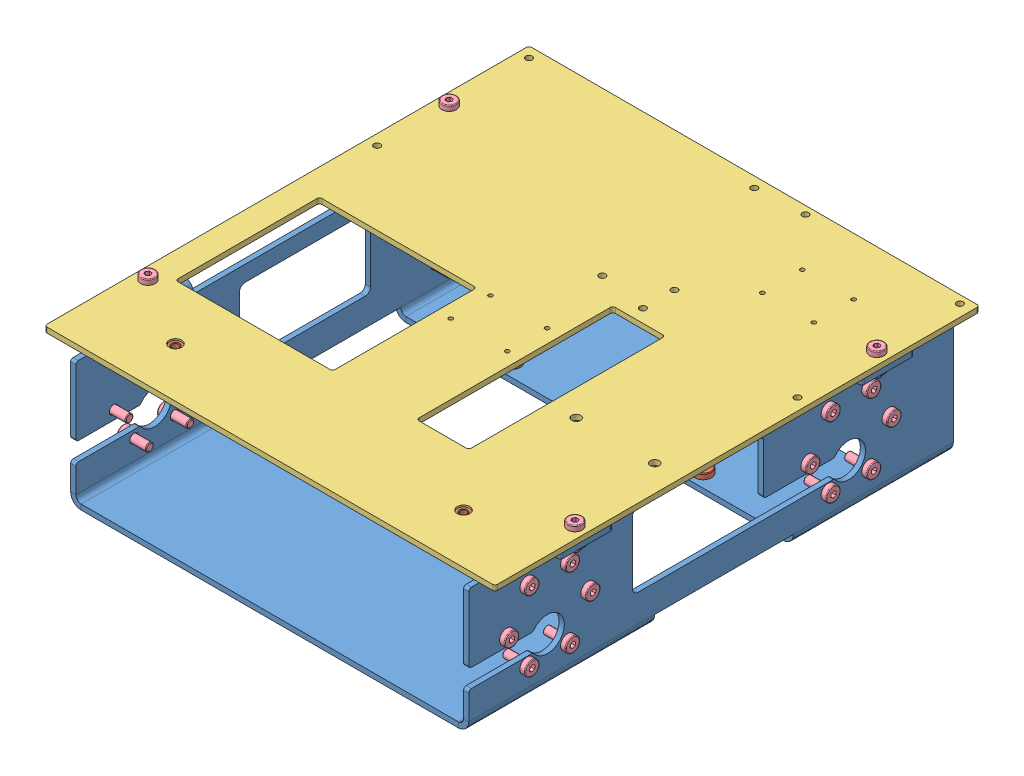
SolidWorks assembly HEL-03-01007-00, configuration Standard. Lengths in mm.
Overall size (172 56 193.5).
44 component instances, 4 part files, 77 mates.
Components (placement in the parent):
- HEL-03-01009-00-1: HEL-03-01009-00 [Standard] at origin size (172 52 193.5)
  - HEL-04-01000-02-1: HEL-04-01000-02 [Standard] at origin size (172 52 193.5)
  - aluminum nut_pmm-11: aluminum nut_pmm [PEM CLA-M3-2 ---N] at (81.5 48 -150) x (0.837169 0 0.546944) z (0.546944 0 -0.837169) size (6.3 3.37 6.3)
  - aluminum nut_pmm-12: aluminum nut_pmm [PEM CLA-M3-2 ---N] at (81.5 48 -35) x (0.837169 0 0.546944) z (0.546944 0 -0.837169) size (6.3 3.37 6.3)
  - aluminum nut_pmm-13: aluminum nut_pmm [PEM CLA-M3-2 ---N] at (-81.5 48 -150) x (0.837169 0 0.546944) z (0.546944 0 -0.837169) size (6.3 3.37 6.3)
  - aluminum nut_pmm-14: aluminum nut_pmm [PEM CLA-M3-2 ---N] at (-81.5 48 -35) x (0.837169 0 0.546944) z (0.546944 0 -0.837169) size (6.3 3.37 6.3)
  - aluminum nut_pmm-15: aluminum nut_pmm [PEM CLA-M3-2 ---N] at (29 6 -191.5) x (1 0 0) z (0 -1 0) size (6.3 3.37 6.3)
  - aluminum nut_pmm-16: aluminum nut_pmm [PEM CLA-M3-2 ---N] at (-29 6 -191.5) x (1 0 0) z (0 -1 0) size (6.3 3.37 6.3)
  - aluminum nut_pmm-17: aluminum nut_pmm [PEM CLA-M3-2 ---N] at (-36.5 0 -129) size (6.3 3.37 6.3)
  - aluminum nut_pmm-18: aluminum nut_pmm [PEM CLA-M3-2 ---N] at (-36.5 0 -66) size (6.3 3.37 6.3)
  - aluminum nut_pmm-19: aluminum nut_pmm [PEM CLA-M3-2 ---N] at (36.5 0 -66) size (6.3 3.37 6.3)
  - aluminum nut_pmm-20: aluminum nut_pmm [PEM CLA-M3-2 ---N] at (36.5 0 -129) x (-0.993512 0 -0.113726) z (0.113726 0 -0.993512) size (6.3 3.37 6.3)
- HEL-03-01010-00-1: HEL-03-01010-00 [Standard] at (0 50 -92.5) size (172 4 185)
  - HEL-04-01010-01-1: HEL-04-01010-01 [Standard] at origin size (172 2 185)
  - aluminum nut_pmm-1: aluminum nut_pmm [PEM CLA-M3-2 ---N] at (55 0 73.5) x (0.837169 0 0.546944) z (0.546944 0 -0.837169) size (6.3 3.37 6.3)
  - aluminum nut_pmm-2: aluminum nut_pmm [PEM CLA-M3-2 ---N] at (-55 0 73.5) x (0.837169 0 0.546944) z (0.546944 0 -0.837169) size (6.3 3.37 6.3)
- socket head thin cap screw_din-1: socket head thin cap screw_din [DIN 7984 - M3 x 8 --- 8N] at (-81.5 54 -35) x (0 -1 0) z (-0.091641 0 0.995792) size (10 5.5 5.5)
- socket head thin cap screw_din-6: socket head thin cap screw_din [DIN 7984 - M3 x 8 --- 8N] at (-78 36.4234 -37.75) size (10 5.5 5.5)
- socket head thin cap screw_din-7: socket head thin cap screw_din [DIN 7984 - M3 x 8 --- 8N] at (-78 36.4234 -22.25) size (10 5.5 5.5)
- socket head thin cap screw_din-8: socket head thin cap screw_din [DIN 7984 - M3 x 8 --- 8N] at (-78 23 -45.5) size (10 5.5 5.5)
- socket head thin cap screw_din-9: socket head thin cap screw_din [DIN 7984 - M3 x 8 --- 8N] at (-78 23 -14.5) size (10 5.5 5.5)
- socket head thin cap screw_din-10: socket head thin cap screw_din [DIN 7984 - M3 x 8 --- 8N] at (-78 9.5766 -22.25) size (10 5.5 5.5)
- socket head thin cap screw_din-11: socket head thin cap screw_din [DIN 7984 - M3 x 8 --- 8N] at (-78 9.5766 -37.75) size (10 5.5 5.5)
- socket head thin cap screw_din-12: socket head thin cap screw_din [DIN 7984 - M3 x 8 --- 8N] at (-78 9.5766 -137.25) size (10 5.5 5.5)
- socket head thin cap screw_din-13: socket head thin cap screw_din [DIN 7984 - M3 x 8 --- 8N] at (-78 9.5766 -152.75) size (10 5.5 5.5)
- socket head thin cap screw_din-14: socket head thin cap screw_din [DIN 7984 - M3 x 8 --- 8N] at (-78 23 -160.5) size (10 5.5 5.5)
- socket head thin cap screw_din-15: socket head thin cap screw_din [DIN 7984 - M3 x 8 --- 8N] at (-78 36.4234 -152.75) size (10 5.5 5.5)
- socket head thin cap screw_din-16: socket head thin cap screw_din [DIN 7984 - M3 x 8 --- 8N] at (-78 36.4234 -137.25) size (10 5.5 5.5)
- socket head thin cap screw_din-17: socket head thin cap screw_din [DIN 7984 - M3 x 8 --- 8N] at (-78 23 -129.5) size (10 5.5 5.5)
- socket head thin cap screw_din-18: socket head thin cap screw_din [DIN 7984 - M3 x 8 --- 8N] at (78 36.4234 -37.75) x (-1 0 0) z (0 0.924225 0.381849) size (10 5.5 5.5)
- socket head thin cap screw_din-19: socket head thin cap screw_din [DIN 7984 - M3 x 8 --- 8N] at (78 36.4234 -22.25) x (-1 0 0) z (0 0.924225 0.381849) size (10 5.5 5.5)
- socket head thin cap screw_din-20: socket head thin cap screw_din [DIN 7984 - M3 x 8 --- 8N] at (78 23 -14.5) x (-1 0 0) z (0 0.924225 0.381849) size (10 5.5 5.5)
- socket head thin cap screw_din-21: socket head thin cap screw_din [DIN 7984 - M3 x 8 --- 8N] at (78 9.5766 -22.25) x (-1 0 0) z (0 0.924225 0.381849) size (10 5.5 5.5)
- socket head thin cap screw_din-22: socket head thin cap screw_din [DIN 7984 - M3 x 8 --- 8N] at (78 9.5766 -37.75) x (-1 0 0) z (0 0.924225 0.381849) size (10 5.5 5.5)
- socket head thin cap screw_din-23: socket head thin cap screw_din [DIN 7984 - M3 x 8 --- 8N] at (78 23 -45.5) x (-1 0 0) z (0 0.924225 0.381849) size (10 5.5 5.5)
- socket head thin cap screw_din-24: socket head thin cap screw_din [DIN 7984 - M3 x 8 --- 8N] at (78 9.5766 -137.25) x (-1 0 0) z (0 0.924225 0.381849) size (10 5.5 5.5)
- socket head thin cap screw_din-25: socket head thin cap screw_din [DIN 7984 - M3 x 8 --- 8N] at (78 9.5766 -152.75) x (-1 0 0) z (0 0.924225 0.381849) size (10 5.5 5.5)
- socket head thin cap screw_din-26: socket head thin cap screw_din [DIN 7984 - M3 x 8 --- 8N] at (78 23 -160.5) x (-1 0 0) z (0 0.924225 0.381849) size (10 5.5 5.5)
- socket head thin cap screw_din-27: socket head thin cap screw_din [DIN 7984 - M3 x 8 --- 8N] at (78 36.4234 -152.75) x (-1 0 0) z (0 0.924225 0.381849) size (10 5.5 5.5)
- socket head thin cap screw_din-28: socket head thin cap screw_din [DIN 7984 - M3 x 8 --- 8N] at (78 36.4234 -137.25) x (-1 0 0) z (0 0.924225 0.381849) size (10 5.5 5.5)
- socket head thin cap screw_din-29: socket head thin cap screw_din [DIN 7984 - M3 x 8 --- 8N] at (78 23 -129.5) x (-1 0 0) z (0 0.924225 0.381849) size (10 5.5 5.5)
- socket head thin cap screw_din-30: socket head thin cap screw_din [DIN 7984 - M3 x 8 --- 8N] at (-81.5 54 -150) x (0 -1 0) z (0 0 1) size (10 5.5 5.5)
- socket head thin cap screw_din-31: socket head thin cap screw_din [DIN 7984 - M3 x 8 --- 8N] at (81.5 54 -150.3) x (0 -1 0) z (0 0 1) size (10 5.5 5.5)
- socket head thin cap screw_din-32: socket head thin cap screw_din [DIN 7984 - M3 x 8 --- 8N] at (81.5 54 -35) x (0 -1 0) z (0 0 1) size (10 5.5 5.5)
Mates (geometry in assembly coordinates):
- Deckungsgleich1: coincident aligned: plane of HEL-03-01009-00-1/HEL-04-01000-02-1 through (86 50 -25) normal (1 0 0); plane of HEL-03-01010-00-1/HEL-04-01010-01-1 through (86 52 -185) normal (1 0 0)
- Deckungsgleich2: coincident aligned: plane of HEL-03-01009-00-1/HEL-04-01000-02-1 through (72 -2 0) normal (0 0 1); plane of HEL-03-01010-00-1/HEL-04-01010-01-1 through (-86 52 0) normal (0 0 1)
- Deckungsgleich3: coincident anti-aligned: plane of HEL-03-01009-00-1/HEL-04-01000-02-1 through (0 50 0) normal (0 1 0); plane of HEL-03-01010-00-1/HEL-04-01010-01-1 through (0 50 -92.5) normal (0 -1 0)
- Konzentrisch1: concentric aligned: cylinder of HEL-03-01009-00-1/aluminum nut_pmm-4 through (81.5 47.7366 -150) axis (0 1 0) radius 3.15; cylinder of aluminum nut_pmm-2 through (81.3683 47.7366 -150) axis (0 1 0) radius 3.15
- Deckungsgleich4: coincident anti-aligned: plane of HEL-03-01009-00-1/HEL-04-01000-02-1 through (0 48 -185) normal (0 -1 0); plane of aluminum nut_pmm-2 through (79.2407 47.7366 -149.7606) normal (0 1 0)
- Konzentrisch2: concentric aligned: cylinder of HEL-03-01009-00-1/aluminum nut_pmm-4 through (81.5 47.7366 -150) axis (0 1 0) radius 3.15; cylinder of aluminum nut_pmm-3 through (81.5 47.7366 -150) axis (0 1 0) radius 3.15
- Deckungsgleich5: coincident anti-aligned: plane of HEL-03-01009-00-1/HEL-04-01000-02-1 through (0 48 -185) normal (0 -1 0); plane of aluminum nut_pmm-3 through (83.2924 47.7366 -148.829) normal (0 1 0)
- Konzentrisch3: concentric aligned: cylinder of HEL-03-01009-00-1/HEL-04-01000-02-1 through (81.5 50 -35) axis (0 1 0) radius 2.395; cylinder of aluminum nut_pmm-4 through (81.5 47.7366 -35) axis (0 1 0) radius 3.15
- Deckungsgleich6: coincident anti-aligned: plane of HEL-03-01009-00-1/HEL-04-01000-02-1 through (0 48 0) normal (0 -1 0); plane of aluminum nut_pmm-4 through (83.2924 47.7366 -33.829) normal (0 1 0)
- Konzentrisch4: concentric aligned: cylinder of HEL-03-01009-00-1/HEL-04-01000-02-1 through (-81.5 50 -150) axis (0 1 0) radius 2.395; cylinder of aluminum nut_pmm-5 through (-81.5 47.7366 -150) axis (0 1 0) radius 3.15
- Deckungsgleich7: coincident anti-aligned: plane of HEL-03-01009-00-1/HEL-04-01000-02-1 through (0 48 -185) normal (0 -1 0); plane of aluminum nut_pmm-5 through (-79.7076 47.7366 -148.829) normal (0 1 0)
- Konzentrisch5: concentric aligned: cylinder of HEL-03-01009-00-1/HEL-04-01000-02-1 through (-81.5 50 -35) axis (0 1 0) radius 2.395; cylinder of aluminum nut_pmm-6 through (-81.5 47.7366 -35) axis (0 1 0) radius 3.15
- Deckungsgleich8: coincident anti-aligned: plane of HEL-03-01009-00-1/HEL-04-01000-02-1 through (0 48 0) normal (0 -1 0); plane of aluminum nut_pmm-6 through (-79.7076 47.7366 -33.829) normal (0 1 0)
- Konzentrisch6: concentric aligned: cylinder of HEL-03-01010-00-1/HEL-04-01010-01-1 through (-81.5 52 -35) axis (0 1 0) radius 1.9; cylinder of socket head thin cap screw_din-1 through (-81.5 85.75 -35) axis (0 1 0) radius 2.75
- Deckungsgleich9: coincident anti-aligned: plane of HEL-03-01010-00-1/HEL-04-01010-01-1 through (0 52 -92.5) normal (0 1 0); plane of socket head thin cap screw_din-1 through (-78.7616 52 -34.748) normal (0 -1 0)
- Konzentrisch7: concentric aligned: cylinder of HEL-03-01010-00-1/HEL-04-01010-01-1 through (55 52 -19) axis (0 1 0) radius 2.395; cylinder of aluminum nut_pmm-7 through (81 49.7366 -15) axis (0 1 0) radius 3.15
- Deckungsgleich10: coincident anti-aligned: plane of HEL-03-01010-00-1/HEL-04-01010-01-1 through (0 50 -92.5) normal (0 -1 0); plane of aluminum nut_pmm-7 through (82.7924 49.7366 -13.829) normal (0 1 0)
- Konzentrisch8: concentric aligned: cylinder of HEL-03-01010-00-1/HEL-04-01010-01-1 through (-55 52 -19) axis (0 1 0) radius 2.395; cylinder of aluminum nut_pmm-8 through (-55 49.7366 -19) axis (0 1 0) radius 3.15
- Deckungsgleich11: coincident anti-aligned: plane of HEL-03-01010-00-1/HEL-04-01010-01-1 through (0 50 -92.5) normal (0 -1 0); plane of aluminum nut_pmm-8 through (-53.2601 49.7366 -20.2476) normal (0 1 0)
- Konzentrisch9: concentric anti-aligned: cylinder of HEL-03-01009-00-1/HEL-04-01000-02-1 through (-29 6 -193.5) axis (0 0 1) radius 2.395; cylinder of aluminum nut_pmm-9 through (-29 6 -190.7366) axis (0 0 -1) radius 3.15
- Deckungsgleich12: coincident anti-aligned: plane of HEL-03-01009-00-1/HEL-04-01000-02-1 through (0 0 -191.5) normal (0 0 1); plane of aluminum nut_pmm-9 through (-26.859 6 -190.7366) normal (0 0 -1)
- Konzentrisch10: concentric anti-aligned: cylinder of HEL-03-01009-00-1/HEL-04-01000-02-1 through (29 6 -193.5) axis (0 0 1) radius 2.395; cylinder of aluminum nut_pmm-10 through (29 6 -190.7366) axis (0 0 -1) radius 3.15
- Deckungsgleich13: coincident anti-aligned: plane of HEL-03-01009-00-1/HEL-04-01000-02-1 through (0 0 -191.5) normal (0 0 1); plane of aluminum nut_pmm-10 through (31.141 6 -190.7366) normal (0 0 -1)
- Konzentrisch11: concentric anti-aligned: cylinder of HEL-03-01009-00-1/HEL-04-01000-02-1 through (76 36.4234 -37.75) axis (1 0 0) radius 1.7; cylinder of socket head thin cap screw_din-6 through (-109.75 36.4234 -37.75) axis (-1 0 0) radius 2.75
- Deckungsgleich14: coincident anti-aligned: plane of HEL-03-01009-00-1/HEL-04-01000-02-1 through (-76 0 -185) normal (-1 0 0); plane of socket head thin cap screw_din-6 through (-76 39.1734 -37.75) normal (1 0 0)
- Konzentrisch12: concentric anti-aligned: cylinder of HEL-03-01009-00-1/HEL-04-01000-02-1 through (76 36.4234 -22.25) axis (1 0 0) radius 1.7; cylinder of socket head thin cap screw_din-7 through (-109.75 36.4234 -22.25) axis (-1 0 0) radius 2.75
- Deckungsgleich15: coincident anti-aligned: plane of HEL-03-01009-00-1/HEL-04-01000-02-1 through (-76 0 -185) normal (-1 0 0); plane of socket head thin cap screw_din-7 through (-76 39.1734 -22.25) normal (1 0 0)
- Konzentrisch13: concentric anti-aligned: cylinder of HEL-03-01009-00-1/HEL-04-01000-02-1 through (76 23 -45.5) axis (1 0 0) radius 1.7; cylinder of socket head thin cap screw_din-8 through (-109.75 23 -45.5) axis (-1 0 0) radius 2.75
- Deckungsgleich16: coincident anti-aligned: plane of HEL-03-01009-00-1/HEL-04-01000-02-1 through (-76 0 -185) normal (-1 0 0); plane of socket head thin cap screw_din-8 through (-76 25.75 -45.5) normal (1 0 0)
- Konzentrisch14: concentric anti-aligned: cylinder of HEL-03-01009-00-1/HEL-04-01000-02-1 through (76 23 -14.5) axis (1 0 0) radius 1.7; cylinder of socket head thin cap screw_din-9 through (-109.75 23 -14.5) axis (-1 0 0) radius 2.75
- Deckungsgleich17: coincident anti-aligned: plane of HEL-03-01009-00-1/HEL-04-01000-02-1 through (-76 0 -185) normal (-1 0 0); plane of socket head thin cap screw_din-9 through (-76 25.75 -14.5) normal (1 0 0)
- Konzentrisch15: concentric anti-aligned: cylinder of HEL-03-01009-00-1/HEL-04-01000-02-1 through (76 9.5766 -22.25) axis (1 0 0) radius 1.7; cylinder of socket head thin cap screw_din-10 through (-109.75 9.5766 -22.25) axis (-1 0 0) radius 2.75
- Deckungsgleich18: coincident anti-aligned: plane of HEL-03-01009-00-1/HEL-04-01000-02-1 through (-76 0 -185) normal (-1 0 0); plane of socket head thin cap screw_din-10 through (-76 12.3266 -22.25) normal (1 0 0)
- Konzentrisch16: concentric anti-aligned: cylinder of HEL-03-01009-00-1/HEL-04-01000-02-1 through (76 9.5766 -37.75) axis (1 0 0) radius 1.7; cylinder of socket head thin cap screw_din-11 through (-109.75 9.5766 -37.75) axis (-1 0 0) radius 2.75
- Deckungsgleich19: coincident anti-aligned: plane of HEL-03-01009-00-1/HEL-04-01000-02-1 through (-76 0 -185) normal (-1 0 0); plane of socket head thin cap screw_din-11 through (-76 12.3266 -37.75) normal (1 0 0)
- Konzentrisch17: concentric anti-aligned: cylinder of HEL-03-01009-00-1/HEL-04-01000-02-1 through (76 9.5766 -137.25) axis (1 0 0) radius 1.7; cylinder of socket head thin cap screw_din-12 through (-109.75 9.5766 -137.25) axis (-1 0 0) radius 2.75
- Deckungsgleich20: coincident anti-aligned: plane of HEL-03-01009-00-1/HEL-04-01000-02-1 through (-76 0 -185) normal (-1 0 0); plane of socket head thin cap screw_din-12 through (-76 12.3266 -137.25) normal (1 0 0)
- Konzentrisch18: concentric anti-aligned: cylinder of HEL-03-01009-00-1/HEL-04-01000-02-1 through (76 9.5766 -152.75) axis (1 0 0) radius 1.7; cylinder of socket head thin cap screw_din-13 through (-109.75 9.5766 -152.75) axis (-1 0 0) radius 2.75
- Deckungsgleich21: coincident anti-aligned: plane of HEL-03-01009-00-1/HEL-04-01000-02-1 through (-76 0 -185) normal (-1 0 0); plane of socket head thin cap screw_din-13 through (-76 12.3266 -152.75) normal (1 0 0)
- Konzentrisch19: concentric anti-aligned: cylinder of HEL-03-01009-00-1/HEL-04-01000-02-1 through (76 23 -160.5) axis (1 0 0) radius 1.7; cylinder of socket head thin cap screw_din-14 through (-109.75 23 -160.5) axis (-1 0 0) radius 2.75
- Deckungsgleich22: coincident anti-aligned: plane of HEL-03-01009-00-1/HEL-04-01000-02-1 through (-76 0 -185) normal (-1 0 0); plane of socket head thin cap screw_din-14 through (-76 25.75 -160.5) normal (1 0 0)
- Konzentrisch20: concentric anti-aligned: cylinder of HEL-03-01009-00-1/HEL-04-01000-02-1 through (76 36.4234 -152.75) axis (1 0 0) radius 1.7; cylinder of socket head thin cap screw_din-15 through (-109.75 36.4234 -152.75) axis (-1 0 0) radius 2.75
- Deckungsgleich23: coincident anti-aligned: plane of HEL-03-01009-00-1/HEL-04-01000-02-1 through (-76 0 -185) normal (-1 0 0); plane of socket head thin cap screw_din-15 through (-76 39.1734 -152.75) normal (1 0 0)
- Konzentrisch21: concentric anti-aligned: cylinder of HEL-03-01009-00-1/HEL-04-01000-02-1 through (76 36.4234 -137.25) axis (1 0 0) radius 1.7; cylinder of socket head thin cap screw_din-16 through (-109.75 36.4234 -137.25) axis (-1 0 0) radius 2.75
- Deckungsgleich24: coincident anti-aligned: plane of HEL-03-01009-00-1/HEL-04-01000-02-1 through (-76 0 -185) normal (-1 0 0); plane of socket head thin cap screw_din-16 through (-76 39.1734 -137.25) normal (1 0 0)
- Konzentrisch22: concentric anti-aligned: cylinder of HEL-03-01009-00-1/HEL-04-01000-02-1 through (76 23 -129.5) axis (1 0 0) radius 1.7; cylinder of socket head thin cap screw_din-17 through (-109.75 23 -129.5) axis (-1 0 0) radius 2.75
- Deckungsgleich25: coincident anti-aligned: plane of HEL-03-01009-00-1/HEL-04-01000-02-1 through (-76 0 -185) normal (-1 0 0); plane of socket head thin cap screw_din-17 through (-76 25.75 -129.5) normal (1 0 0)
- Konzentrisch23: concentric aligned: cylinder of HEL-03-01009-00-1/HEL-04-01000-02-1 through (76 36.4234 -37.75) axis (1 0 0) radius 1.7; cylinder of socket head thin cap screw_din-18 through (109.75 36.4234 -37.75) axis (1 0 0) radius 2.75
- Deckungsgleich26: coincident anti-aligned: plane of HEL-03-01009-00-1/HEL-04-01000-02-1 through (76 0 -185) normal (1 0 0); plane of socket head thin cap screw_din-18 through (76 35.3733 -35.2084) normal (-1 0 0)
- Konzentrisch24: concentric aligned: cylinder of HEL-03-01009-00-1/HEL-04-01000-02-1 through (76 36.4234 -22.25) axis (1 0 0) radius 1.7; cylinder of socket head thin cap screw_din-19 through (109.75 36.4234 -22.25) axis (1 0 0) radius 2.75
- Deckungsgleich27: coincident anti-aligned: plane of HEL-03-01009-00-1/HEL-04-01000-02-1 through (76 0 -185) normal (1 0 0); plane of socket head thin cap screw_din-19 through (76 35.3733 -19.7084) normal (-1 0 0)
- Konzentrisch25: concentric aligned: cylinder of HEL-03-01009-00-1/HEL-04-01000-02-1 through (76 23 -14.5) axis (1 0 0) radius 1.7; cylinder of socket head thin cap screw_din-20 through (109.75 23 -14.5) axis (1 0 0) radius 2.75
- Deckungsgleich28: coincident anti-aligned: plane of HEL-03-01009-00-1/HEL-04-01000-02-1 through (76 0 -185) normal (1 0 0); plane of socket head thin cap screw_din-20 through (76 21.9499 -11.9584) normal (-1 0 0)
- Konzentrisch26: concentric aligned: cylinder of HEL-03-01009-00-1/HEL-04-01000-02-1 through (76 9.5766 -22.25) axis (1 0 0) radius 1.7; cylinder of socket head thin cap screw_din-21 through (109.75 9.5766 -22.25) axis (1 0 0) radius 2.75
- Deckungsgleich29: coincident anti-aligned: plane of HEL-03-01009-00-1/HEL-04-01000-02-1 through (76 0 -185) normal (1 0 0); plane of socket head thin cap screw_din-21 through (76 8.5265 -19.7084) normal (-1 0 0)
- Konzentrisch27: concentric aligned: cylinder of HEL-03-01009-00-1/HEL-04-01000-02-1 through (76 9.5766 -37.75) axis (1 0 0) radius 1.7; cylinder of socket head thin cap screw_din-22 through (109.75 9.5766 -37.75) axis (1 0 0) radius 2.75
- Deckungsgleich30: coincident anti-aligned: plane of HEL-03-01009-00-1/HEL-04-01000-02-1 through (76 0 -185) normal (1 0 0); plane of socket head thin cap screw_din-22 through (76 8.5265 -35.2084) normal (-1 0 0)
- Konzentrisch28: concentric aligned: cylinder of HEL-03-01009-00-1/HEL-04-01000-02-1 through (76 23 -45.5) axis (1 0 0) radius 1.7; cylinder of socket head thin cap screw_din-23 through (109.75 23 -45.5) axis (1 0 0) radius 2.75
- Deckungsgleich31: coincident anti-aligned: plane of HEL-03-01009-00-1/HEL-04-01000-02-1 through (76 0 -185) normal (1 0 0); plane of socket head thin cap screw_din-23 through (76 21.9499 -42.9584) normal (-1 0 0)
- Konzentrisch29: concentric aligned: cylinder of HEL-03-01009-00-1/HEL-04-01000-02-1 through (76 9.5766 -137.25) axis (1 0 0) radius 1.7; cylinder of socket head thin cap screw_din-24 through (109.75 9.5766 -137.25) axis (1 0 0) radius 2.75
- Deckungsgleich32: coincident anti-aligned: plane of HEL-03-01009-00-1/HEL-04-01000-02-1 through (76 0 -185) normal (1 0 0); plane of socket head thin cap screw_din-24 through (76 8.5265 -134.7084) normal (-1 0 0)
- Konzentrisch30: concentric aligned: cylinder of HEL-03-01009-00-1/HEL-04-01000-02-1 through (76 9.5766 -152.75) axis (1 0 0) radius 1.7; cylinder of socket head thin cap screw_din-25 through (109.75 9.5766 -152.75) axis (1 0 0) radius 2.75
- Deckungsgleich33: coincident anti-aligned: plane of HEL-03-01009-00-1/HEL-04-01000-02-1 through (76 0 -185) normal (1 0 0); plane of socket head thin cap screw_din-25 through (76 8.5265 -150.2084) normal (-1 0 0)
- Konzentrisch31: concentric aligned: cylinder of HEL-03-01009-00-1/HEL-04-01000-02-1 through (76 23 -160.5) axis (1 0 0) radius 1.7; cylinder of socket head thin cap screw_din-26 through (109.75 23 -160.5) axis (1 0 0) radius 2.75
- Deckungsgleich34: coincident anti-aligned: plane of HEL-03-01009-00-1/HEL-04-01000-02-1 through (76 0 -185) normal (1 0 0); plane of socket head thin cap screw_din-26 through (76 21.9499 -157.9584) normal (-1 0 0)
- Konzentrisch32: concentric aligned: cylinder of HEL-03-01009-00-1/HEL-04-01000-02-1 through (76 36.4234 -152.75) axis (1 0 0) radius 1.7; cylinder of socket head thin cap screw_din-27 through (109.75 36.4234 -152.75) axis (1 0 0) radius 2.75
- Deckungsgleich35: coincident anti-aligned: plane of HEL-03-01009-00-1/HEL-04-01000-02-1 through (76 0 -185) normal (1 0 0); plane of socket head thin cap screw_din-27 through (76 35.3733 -150.2084) normal (-1 0 0)
- Konzentrisch33: concentric aligned: cylinder of HEL-03-01009-00-1/HEL-04-01000-02-1 through (76 36.4234 -137.25) axis (1 0 0) radius 1.7; cylinder of socket head thin cap screw_din-28 through (109.75 36.4234 -137.25) axis (1 0 0) radius 2.75
- Deckungsgleich36: coincident anti-aligned: plane of HEL-03-01009-00-1/HEL-04-01000-02-1 through (76 0 -185) normal (1 0 0); plane of socket head thin cap screw_din-28 through (76 35.3733 -134.7084) normal (-1 0 0)
- Konzentrisch34: concentric aligned: cylinder of HEL-03-01009-00-1/HEL-04-01000-02-1 through (76 23 -129.5) axis (1 0 0) radius 1.7; cylinder of socket head thin cap screw_din-29 through (109.75 23 -129.5) axis (1 0 0) radius 2.75
- Deckungsgleich37: coincident anti-aligned: plane of HEL-03-01009-00-1/HEL-04-01000-02-1 through (76 0 -185) normal (1 0 0); plane of socket head thin cap screw_din-29 through (76 21.9499 -126.9584) normal (-1 0 0)
- Konzentrisch35: concentric aligned: cylinder of HEL-03-01010-00-1/HEL-04-01010-01-1 through (-81.5 52 -150) axis (0 1 0) radius 1.9; cylinder of socket head thin cap screw_din-30 through (-81.5 85.75 -150) axis (0 1 0) radius 2.75
- Deckungsgleich38: coincident anti-aligned: plane of HEL-03-01010-00-1/HEL-04-01010-01-1 through (0 52 -92.5) normal (0 1 0); plane of socket head thin cap screw_din-30 through (-78.75 52 -150) normal (0 -1 0)
- Konzentrisch36: concentric aligned: cylinder of HEL-03-01010-00-1/HEL-04-01010-01-1 through (81.5 52 -150.3) axis (0 1 0) radius 1.7; cylinder of socket head thin cap screw_din-31 through (81.5 85.75 -150.3) axis (0 1 0) radius 2.75
- Deckungsgleich39: coincident anti-aligned: plane of HEL-03-01010-00-1/HEL-04-01010-01-1 through (0 52 -92.5) normal (0 1 0); plane of socket head thin cap screw_din-31 through (84.25 52 -150.3) normal (0 -1 0)
- Konzentrisch37: concentric aligned: cylinder of HEL-03-01010-00-1/HEL-04-01010-01-1 through (81.5 52 -35) axis (0 1 0) radius 1.7; cylinder of socket head thin cap screw_din-32 through (81.5 85.75 -35) axis (0 1 0) radius 2.75
- Deckungsgleich40: coincident anti-aligned: plane of HEL-03-01010-00-1/HEL-04-01010-01-1 through (0 52 -92.5) normal (0 1 0); plane of socket head thin cap screw_din-32 through (84.25 52 -35) normal (0 -1 0)
